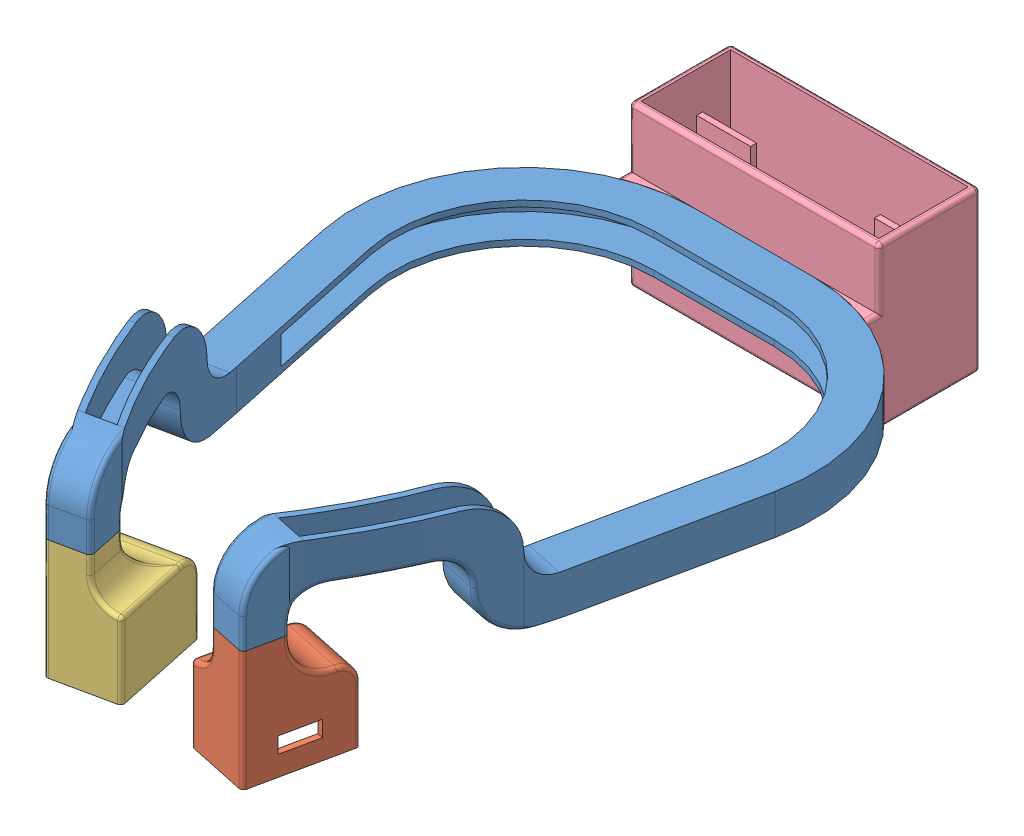
SolidWorks assembly combined-case-it9, configuration Default. Lengths in mm.
Overall size (115 50.8 178.14).
4 component instances, 4 part files, 3 mates.
Components (placement in the parent):
- head-band-it9-1: head-band-it9 [Default] at (65.893 70.3739 37.4781) size (115 31.51 152.74)
- transdux-left-it9-1: transdux-left-it9 [Default] at (65.893 50.3739 37.4781) size (20.96 30 27.51)
- transdux-right-it9-1: transdux-right-it9 [Default] at (65.893 50.3739 37.4781) size (20.96 30 27.51)
- elex-compartment-it9-1: elex-compartment-it9 [Default] at (65.893 75.3739 37.4781) size (62.5 40 28.7)
Mates (geometry in assembly coordinates):
- Coincident1: coincident: point of head-band-it9-1; point of transdux-right-it9-1
- Coincident2: coincident: point of head-band-it9-1; point of transdux-left-it9-1
- Coincident3: coincident anti-aligned: circle of head-band-it9-1; circle of elex-compartment-it9-1
